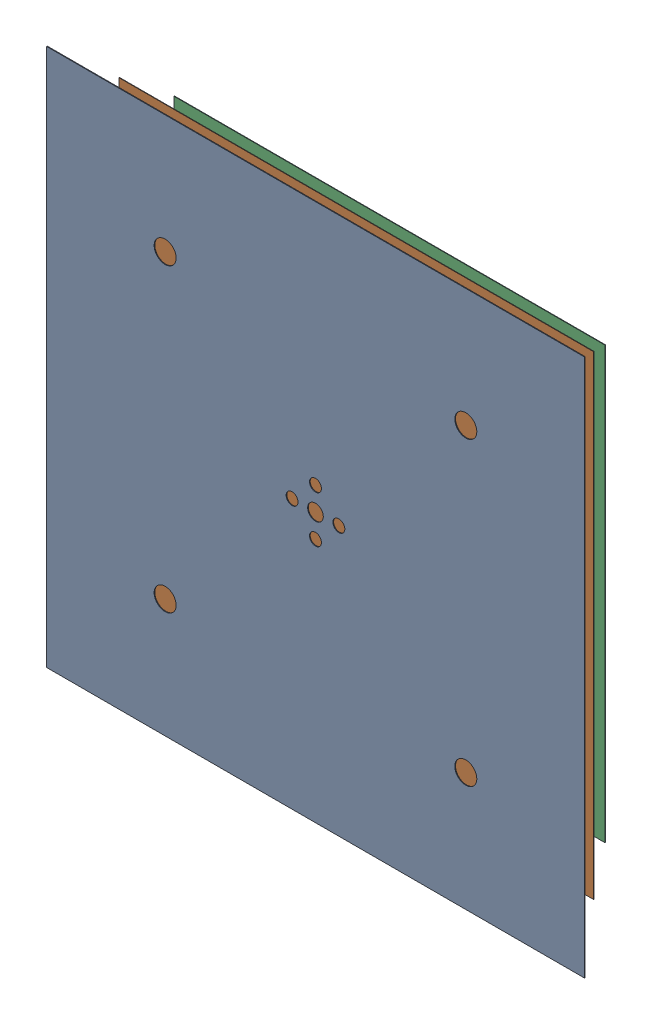
SolidWorks assembly MSR_door, configuration Default. Lengths in mm.
Overall size (3220 3220 551).
4 component instances, 4 part files, 11 mates.
Components (placement in the parent):
- layer1_door-1: layer1_door [Default] at (0 0 1823.7221) size (3220 3220 4)
- layer2_door-2: layer2_door [Default] at (0 0 1580.2221) size (2840 2840 3)
- layer3_door-1: layer3_door [Default] at (0 0 1381.7221) size (2580 2580 3)
- layer5_door-1: layer5_door [Default] at (0 0 1276.7221) size (2160 2160 2)
Mates (geometry in assembly coordinates):
- Distance1: distance = 1610 mm: plane of assembly through (0 0 0) normal (0 1 0); plane of assembly; plane of layer1_door-1 through (-1610 1610 1827.7221) normal (0 1 0)
- Distance2: distance = 1610 mm: plane of assembly through (0 0 0) normal (1 0 0); plane of assembly; plane of layer1_door-1 through (1610 1610 1827.7221) normal (1 0 0)
- Distance3: distance = 1420 mm aligned: plane of layer2_door-2 through (-1420 1420 1583.2221) normal (0 1 0)
- Distance4: distance = 1420 mm: plane of assembly through (0 0 0) normal (1 0 0); plane of assembly; plane of layer2_door-2 through (1420 1420 1583.2221) normal (1 0 0)
- Distance5: distance = 243.5 mm aligned: plane of layer1_door-1 through (0 0 1823.7221) normal (0 0 -1); plane of layer2_door-2 through (0 0 1580.2221) normal (0 0 -1)
- Distance6: distance = 198.5 mm aligned: plane of layer2_door-2 through (0 0 1580.2221) normal (0 0 -1); plane of layer3_door-1 through (0 0 1381.7221) normal (0 0 -1)
- Distance7: distance = 1290 mm: plane of assembly through (0 0 0) normal (0 1 0); plane of assembly; plane of layer3_door-1 through (-1290 1290 1384.7221) normal (0 1 0)
- Distance9: distance = 1290 mm: plane of assembly through (0 0 0) normal (1 0 0); plane of assembly; plane of layer3_door-1 through (-1290 1290 1384.7221) normal (-1 0 0)
- Distance10: distance = 105 mm aligned: plane of layer5_door-1 through (0 0 1276.7221) normal (0 0 -1); plane of layer3_door-1 through (0 0 1381.7221) normal (0 0 -1)
- Distance11: distance = 1080 mm: plane of assembly through (0 0 0) normal (0 1 0); plane of assembly; plane of layer5_door-1 through (-1080 1080 1278.7221) normal (0 1 0)
- Distance12: distance = 1080 mm: plane of assembly through (0 0 0) normal (1 0 0); plane of assembly; plane of layer5_door-1 through (-1080 1080 1278.7221) normal (-1 0 0)
